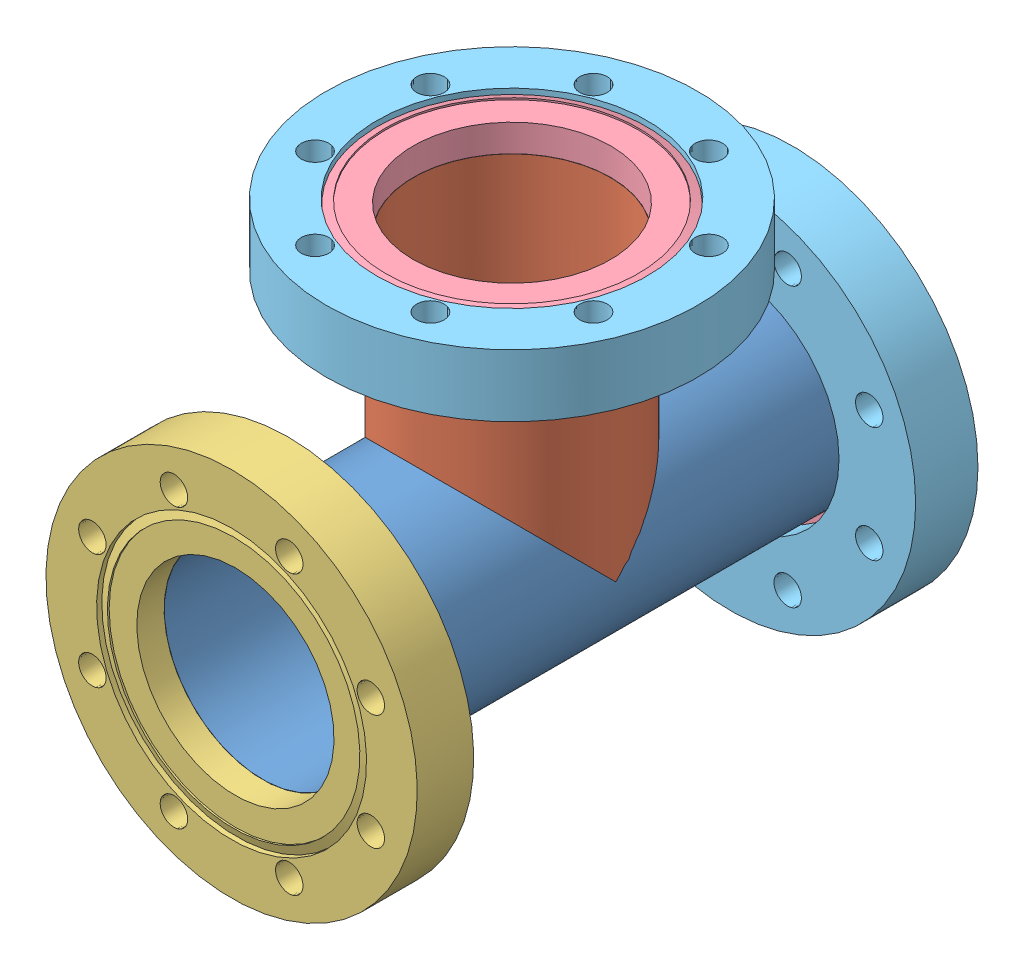
SolidWorks assembly T4-404038, configuration Default. Lengths in mm.
Overall size (113.54 142.49 171.45).
9 component instances, 5 part files, 0 mates.
Components (placement in the parent):
- 404038-001-1: 404038-001 [Default] at origin size (63.51 63.51 152.4)
- 404038-002-1: 404038-002 [Default] at (0 0 76.2) x (1 0 0) z (0 1 0) size (63.5 63.5 78.71)
- 110021 (4.5 X 2.5 NR)_1-1: 110021 (4.5 X 2.5 NR)_1 [Default] at (0 0 161.925) x (0 0 -1) z (1 0 0) size (17.27 113.54 113.54)
- 100021 (4.5 X 2.5 R)_1-1: 100021 (4.5 X 2.5 R)_1 [Default] at (0 73.025 76.2) x (0 1 0) z (0 0 1) size (19.05 113.54 113.54)
  - 100021 (4.5 X 2.5 INS)_1-1: 100021 (4.5 X 2.5 INS)_1 [Default] at origin size (12.04 82.3 82.3)
  - 100021 (4.5 X 2.5 REC)_1-1: 100021 (4.5 X 2.5 REC)_1 [Default] at (-6.35 0 0) x (1 0 0) z (0 0 -1) size (19.05 113.54 113.54)
- 100021 (4.5 X 2.5 R)_1-2: 100021 (4.5 X 2.5 R)_1 [Default] at (0 0 3.175) x (0 0 -1) z (1 0 0) size (19.05 113.54 113.54)
  - 100021 (4.5 X 2.5 INS)_1-1: 100021 (4.5 X 2.5 INS)_1 [Default] at origin size (12.04 82.3 82.3)
  - 100021 (4.5 X 2.5 REC)_1-1: 100021 (4.5 X 2.5 REC)_1 [Default] at (-6.35 0 0) x (1 0 0) z (0 0 -1) size (19.05 113.54 113.54)
